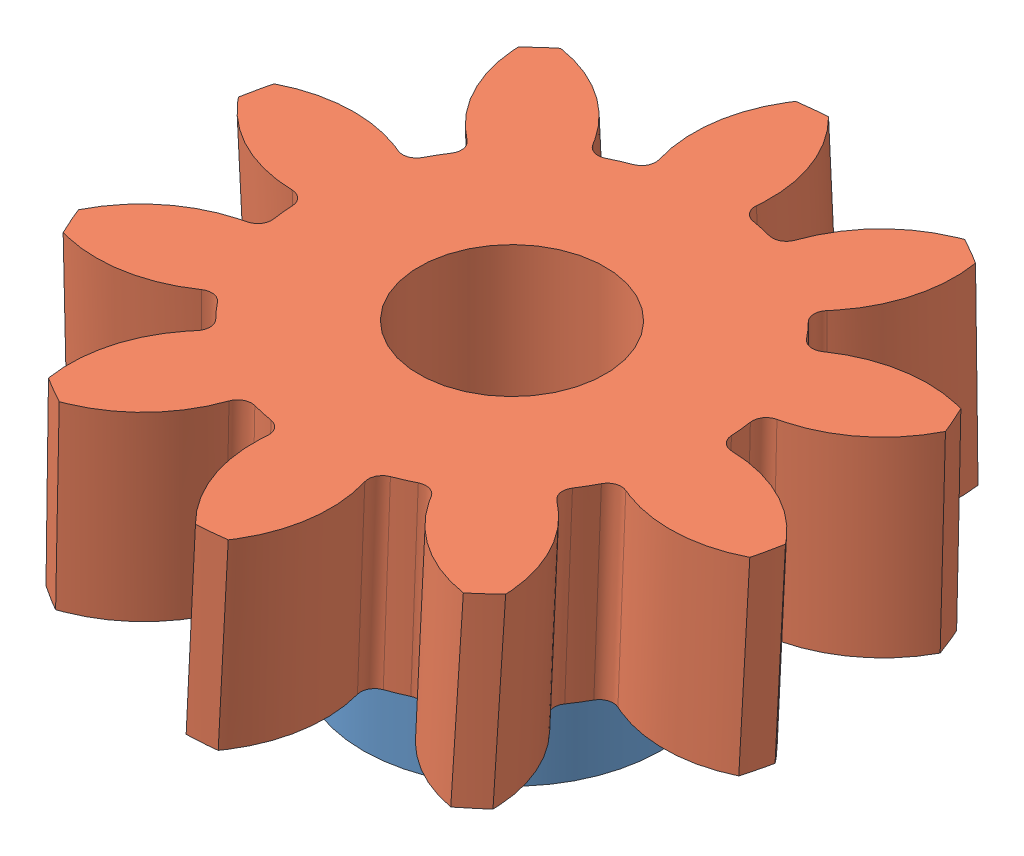
SolidWorks assembly Assem2, configuration Default. Lengths in mm.
Overall size (18.99 8 19.23).
2 component instances, 2 part files, 2 mates.
Components (placement in the parent):
- gear_space-1: gear_space [Default] at (4.2316 2.6988 5.4672) size (8 3 8)
- Metric - RH Helical gear 1.5M 10T 0HA 20PA 5mmFW ---10N75H50L5.0N-1: Metric - RH Helical gear 1.5M 10T 0HA 20PA 5mmFW ---10N75H50L5.0N [Metric - RH Helical gear 1.5M 10T 0HA 20PA 5mmFW ---10N75H50L5.0N] at (4.2316 5.6988 5.4672) x (0 1 0) z (0.072185 0 0.997391) size (5 17.74 18)
Mates (geometry in assembly coordinates):
- Concentric11: concentric: cylinder of gear_space-1 through (4.2316 5.6988 5.4672) axis (0 -1 0) radius 2.5; cylinder of Metric - RH Helical gear 1.5M 10T 0HA 20PA 5mmFW ---10N75H50L5.0N-1 through (4.2316 69.8241 5.4672) axis (0 -1 0) radius 2.5
- Coincident1: coincident anti-aligned: plane of gear_space-1 through (4.2316 5.6988 5.4672) normal (0 1 0); plane of Metric - RH Helical gear 1.5M 10T 0HA 20PA 5mmFW ---10N75H50L5.0N-1 through (4.2316 5.6988 5.4672) normal (0 -1 0)
